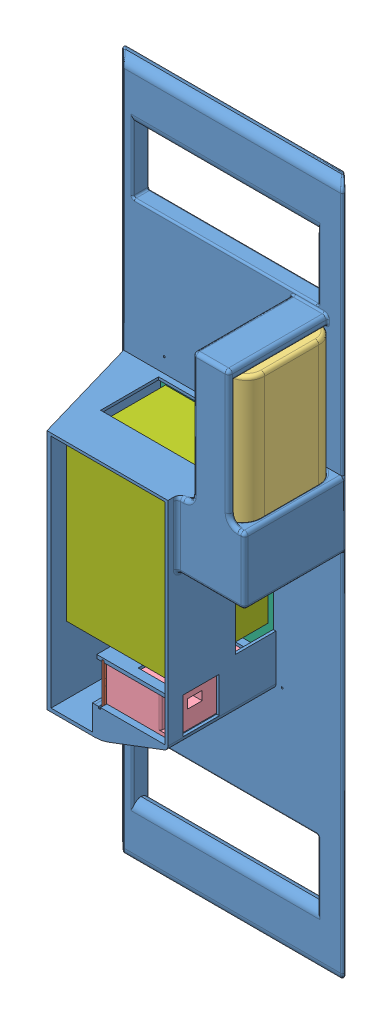
SolidWorks assembly Full Assembly, configuration Default. Lengths in mm.
Overall size (130.66 385.07 69.2).
10 component instances, 9 part files, 12 mates.
Components (placement in the parent):
- Case v6-1: Case v6 [Default] at (117.4281 413.8921 133.5943) size (130.66 385.07 69.2)
- Cover-1: Cover [Default] at (173.812 501.0633 411.8784) x (0 1 0) z (-1 0 0) size (22.5 20 1)
- Part5^Full Assembly-1: Part5^Full Assembly [Default] at origin (virtual)
- Battery-1: Battery [Default] at (245.062 687.4735 403.8783) x (-1 0 0) z (0 -1 0) size (27.5 50 105)
- Part6^Full Assembly-1: Part6^Full Assembly [Default] at origin (virtual)
- AirQualitySensor-1: AirQualitySensor [Default] at (209.812 501.5517 365.3783) x (0 1 0) z (1 0 0) size (20 46 35)
- TempHumidity-1: TempHumidity [Default] at (146.4136 491.5563 378.8783) x (0 0 -1) z (0 -1 0) size (25 17.75 15)
- ScreenPi-1: ScreenPi [Default] at (117.4281 413.8921 133.5943) size (111.5 193 63.5)
  - Screen-1: Screen [Default] at (9.8156 56.5814 211.084) size (111.5 193 8.5)
  - Raspberry Pi-1: Raspberry Pi [Default] at (88.8156 199.0814 219.584) x (-1 0 0) z (0 0 1) size (57 86 55)
Mates (geometry in assembly coordinates):
- Coincident8: coincident anti-aligned: plane of Case v6-1 through (172.8159 499.5633 393.8783) normal (0 1 0); plane of Cover-1 through (172.812 499.5633 401.8784) normal (0 -1 0)
- Coincident9: coincident anti-aligned: plane of Case v6-1 through (117.4281 413.8921 391.8783) normal (0 0 1); plane of Cover-1 through (172.812 499.5633 391.8783) normal (0 0 -1)
- Coincident10: coincident anti-aligned: plane of Case v6-1 through (172.812 521.0633 391.8783) normal (1 0 0); plane of Cover-1 through (172.812 501.0633 411.8784) normal (-1 0 0)
- Coincident11: coincident anti-aligned: plane of Case v6-1 through (240.062 687.4735 408.8783) normal (0 -1 0); plane of Battery-1 through (227.562 687.4735 393.8783) normal (0 1 0)
- Coincident12: coincident anti-aligned: plane of Case v6-1 through (245.062 628.3507 396.3803) normal (-1 0 0); plane of Battery-1 through (245.062 582.4735 393.8783) normal (1 0 0)
- Coincident13: coincident anti-aligned: plane of Case v6-1 through (182.9937 566.9735 353.8783) normal (0 0 1); plane of Battery-1 through (235.062 582.4735 353.8783) normal (0 0 -1)
- Coincident14: coincident anti-aligned: plane of Case v6-1 through (209.812 500.5563 344.6783) normal (-1 0 0); plane of AirQualitySensor-1 through (209.812 501.5517 365.3783) normal (1 0 0)
- Coincident15: coincident anti-aligned: plane of Case v6-1 through (209.812 519.0633 365.3783) normal (0 0 1); plane of AirQualitySensor-1 through (174.812 501.5517 365.3783) normal (0 0 -1)
- Coincident17: coincident anti-aligned: plane of Case v6-1 through (178.1128 486.5563 383.5283) normal (0 1 0); plane of TempHumidity-1 through (146.4136 486.5563 378.8783) normal (0 -1 0)
- Coincident19: coincident anti-aligned: plane of Case v6-1 through (146.4136 617.3507 344.6783) normal (1 0 0); plane of TempHumidity-1 through (146.4136 489.5563 353.8783) normal (-1 0 0)
- Coincident20: coincident anti-aligned: plane of Case v6-1 through (182.9937 566.9735 353.8783) normal (0 0 1); plane of TempHumidity-1 through (164.1636 489.5563 353.8783) normal (0 0 -1)
- Coincident21: coincident anti-aligned: circle of Case v6-1; circle of ScreenPi-1/Screen-1
